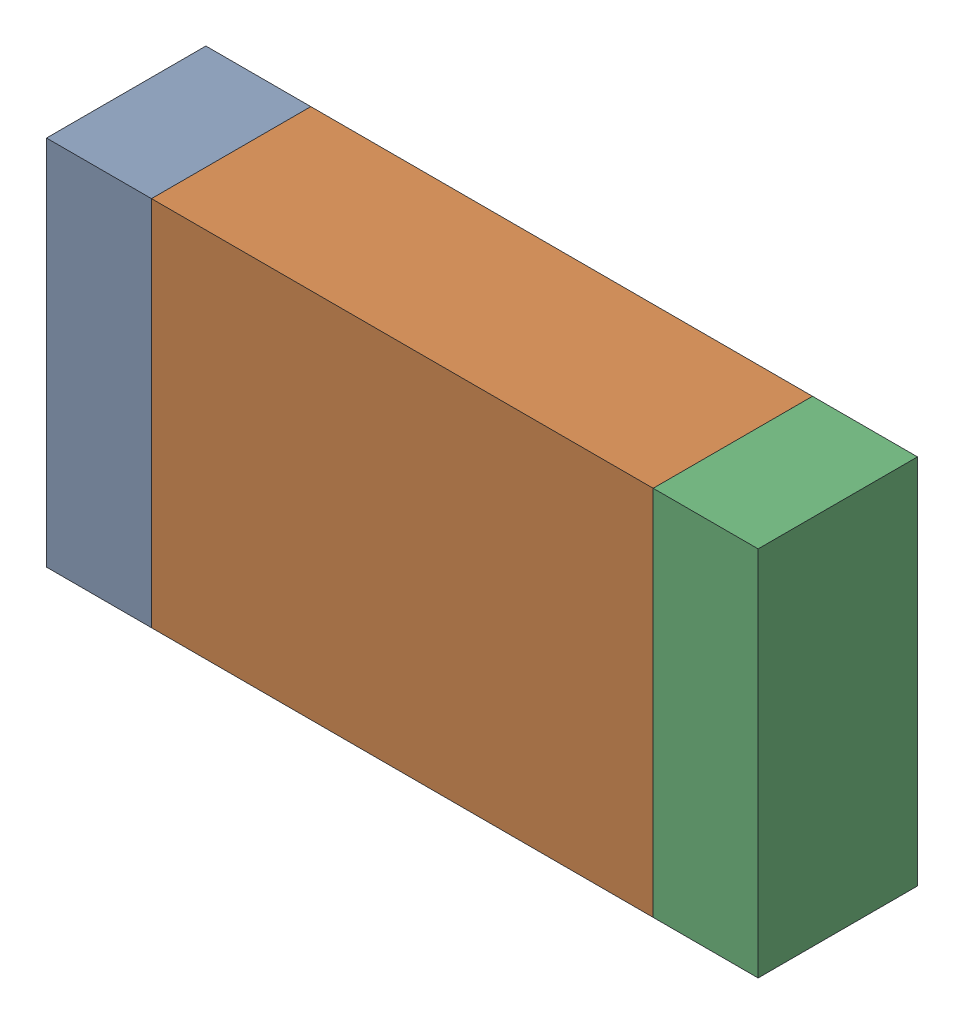
SolidWorks assembly R03-2, configuration Default. Lengths in mm.
Overall size (3.35 1.75 0.75).
6 component instances, 2 part files, 0 mates.
Components (placement in the parent):
- 959206760-2-1: 959206760-2 [Default] at (147.8506 77.6516 0) size (0.49 1.75 0.75)
  - Extruded-64-1: Extruded-64 [Default] at origin size (0.49 1.75 0.75)
- 959206896-2-1: 959206896-2 [Default] at (149.2781 77.6516 0) size (2.36 1.75 0.75)
  - Extruded-65-1: Extruded-65 [Default] at origin size (2.36 1.75 0.75)
- 959206760-2-2: 959206760-2 [Default] at (150.7056 77.6516 0) size (0.49 1.75 0.75)
  - Extruded-64-1: Extruded-64 [Default] at origin size (0.49 1.75 0.75)
